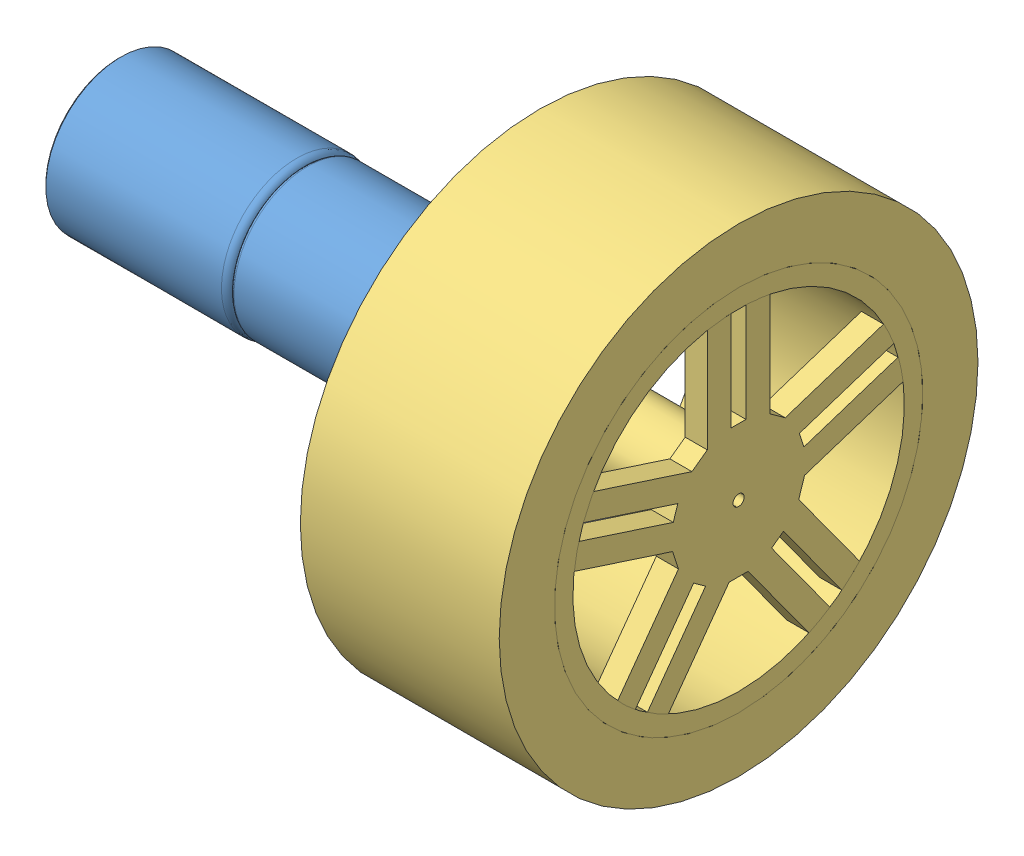
SolidWorks assembly Motor Wheel Assembly, configuration Default. Lengths in mm.
Overall size (84.1 65 65).
3 component instances, 3 part files, 6 mates.
Components (placement in the parent):
- DC Motor-1: DC Motor [Default] at origin size (53.1 20.4 20.4)
- Motor Shaft Coupler-1: Motor Shaft Coupler [Default] at (62.6 0 0) x (0 0 1) z (0 -1 0) size (9 15 9)
- Wheel-1: Wheel [Default] at (84.1 0 0) x (0 0 -1) z (0 1 0) size (65 28.5 65)
Mates (geometry in assembly coordinates):
- Concentric1: concentric aligned: cylinder of DC Motor-1 through (53.1 0 0) axis (-1 0 0) radius 2; cylinder of Motor Shaft Coupler-1 through (53.1 0 0) axis (-1 0 0) radius 2
- Coincident1: coincident anti-aligned: plane of DC Motor-1 through (53.1 0 0) normal (1 0 0); plane of Motor Shaft Coupler-1 through (53.1 0 0) normal (-1 0 0)
- Concentric2: concentric aligned: cylinder of Motor Shaft Coupler-1 through (54.6 0 0) axis (1 0 0) radius 2.7; cylinder of Wheel-1 through (55.6 0 0) axis (1 0 0) radius 2.7
- Concentric3: concentric aligned: cylinder of Motor Shaft Coupler-1 through (54.6 0 0) axis (1 0 0) radius 2.7; cylinder of Wheel-1 through (55.6 0 0) axis (1 0 0) radius 2.7
- Coincident2: coincident anti-aligned: plane of Motor Shaft Coupler-1 through (54.6 2.0561 1.75) normal (0 0 1); plane of Wheel-1 through (55.6 -2.0561 1.75) normal (0 0 -1)
- Coincident3: coincident anti-aligned: circle of Motor Shaft Coupler-1; circle of Wheel-1
